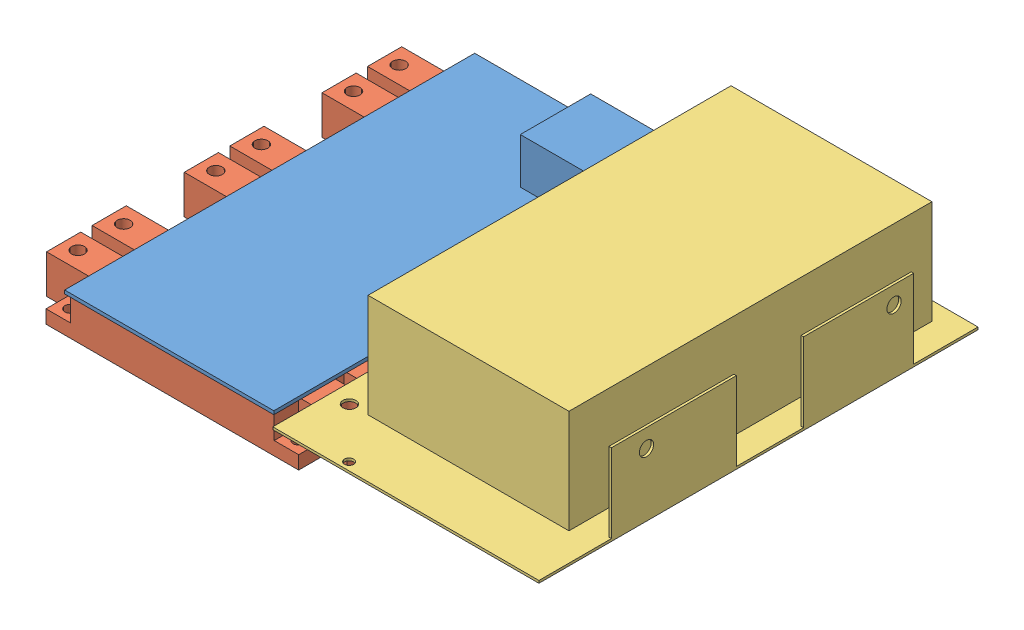
SolidWorks assembly Motor Controller, configuration Default. Lengths in mm.
Overall size (257.5 69.85 212).
5 component instances, 3 part files, 11 mates.
Components (placement in the parent):
- HV Board-1: HV Board [Default] at (41.0841 104.6187 160.3916) size (101 23.65 198)
- IGBT-1: IGBT [Default] at (41.0841 85.9487 226.8916) size (145 18.67 62)
- IGBT-2: IGBT [Default] at (41.0841 85.9487 160.3916) size (145 18.67 62)
- IGBT-3: IGBT [Default] at (41.0841 85.9487 93.8916) size (145 18.67 62)
- Capacitor Board-1: Capacitor Board [Default] at (161.8341 104.6187 159.8916) size (128.5 51.18 212)
Mates (geometry in assembly coordinates):
- Coincident1: coincident aligned: plane of IGBT-1 through (41.0841 104.6187 226.8916) normal (0 1 0); plane of IGBT-2 through (41.0841 104.6187 160.3916) normal (0 1 0)
- Coincident2: coincident aligned: plane of IGBT-2 through (41.0841 104.6187 160.3916) normal (0 1 0); plane of IGBT-3 through (41.0841 104.6187 93.8916) normal (0 1 0)
- Coincident3: coincident anti-aligned: plane of HV Board-1 through (41.0841 104.6187 160.3916) normal (0 -1 0); plane of IGBT-3 through (41.0841 104.6187 93.8916) normal (0 1 0)
- Coincident4: coincident aligned: plane of HV Board-1 through (41.0841 104.6187 160.3916) normal (1 0 0); plane of IGBT-1 through (41.0841 85.9487 226.8916) normal (1 0 0)
- Coincident5: coincident aligned: plane of IGBT-2 through (41.0841 85.9487 160.3916) normal (1 0 0); plane of IGBT-3 through (41.0841 85.9487 93.8916) normal (1 0 0)
- Coincident6: coincident aligned: plane of IGBT-1 through (41.0841 85.9487 226.8916) normal (1 0 0); plane of IGBT-2 through (41.0841 85.9487 160.3916) normal (1 0 0)
- Distance1: distance = 4.5 mm anti-aligned: plane of IGBT-3 through (41.0841 92.3987 124.8916) normal (0 0 1); plane of IGBT-2 through (41.0841 92.3987 129.3916) normal (0 0 -1)
- Distance2: distance = 4.5 mm anti-aligned: plane of IGBT-1 through (41.0841 92.3987 195.8916) normal (0 0 -1); plane of IGBT-2 through (41.0841 92.3987 191.3916) normal (0 0 1)
- Coincident9: coincident aligned: plane of HV Board-1 through (41.0841 104.6187 160.3916) normal (0 0 1); plane of IGBT-2 through (41.0841 85.9487 160.3916) normal (0 0 1)
- Coincident13: coincident aligned: circle of IGBT-1; circle of Capacitor Board-1
- Parallel1: parallel anti-aligned: line of HV Board-1 through (91.5841 106.2687 259.3916) axis (0 0 -1); line of Capacitor Board-1 through (97.5841 105.7987 53.8916) axis (0 0 1)
